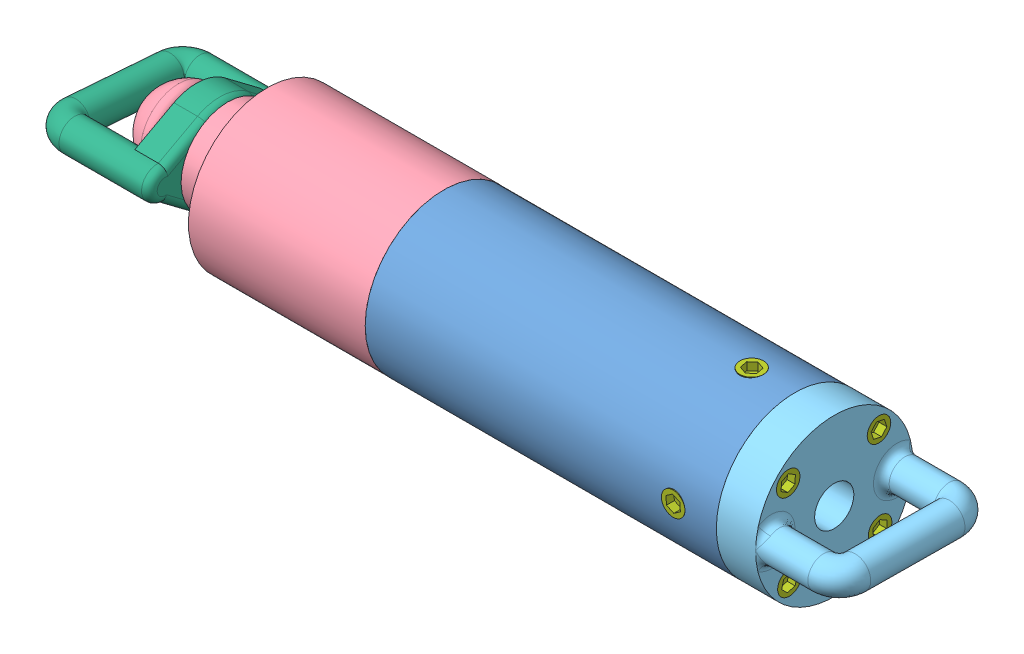
SolidWorks assembly Ensamblaje original vista conjunta, configuration Predeterminado. Lengths in mm.
Overall size (103.35 23.38 23.38).
16 component instances, 7 part files, 18 mates.
Components (placement in the parent):
- Elemento 1-1: Elemento 1 [Predeterminado] at (-42.454 6.1684 44.721) size (44.72 20 20)
- Elemento 2-1: Elemento 2 [Predeterminado] at (-6.254 6.1684 44.721) x (1 0 0) z (0 -0.9988 0.048973) size (5 12.09 12.06)
- Elemento 3-1: Elemento 3 [Predeterminado] at (-3.254 6.1684 44.721) x (-1 0 0) z (0 -1 0) size (57.07 12 12)
- Elemento 4-1: Elemento 4 [Predeterminado] at (-42.454 6.1684 44.721) x (-1 0 0) z (0 0.982476 -0.186391) size (37.67 20 20)
- Elemento 5-1: Elemento 5 [Predeterminado] at (2.246 6.1684 44.721) x (1 0 0) z (0 0.009186 0.999958) size (15.81 20 20)
- Elemento 6-1: Elemento 6 [Predeterminado] at (-69.954 6.1684 44.721) x (-1 0 0) z (0 0.0753 0.997161) size (15.5 12.01 20.01)
- Tornillo-2: Tornillo [Predeterminado] at (-3.254 6.1684 34.721) x (0 0 1) z (-0.99419 -0.107636 0) size (6.53 3 3)
- Tornillo-3: Tornillo [Predeterminado] at (-3.254 6.1684 54.721) x (0 0 -1) z (0.285128 -0.958489 0) size (6.53 3 3)
- Tornillo-4: Tornillo [Predeterminado] at (-3.254 16.1684 44.721) x (0 -1 0) z (0.385697 0 0.922626) size (6.53 3 3)
- Tornillo-6: Tornillo [Predeterminado] at (-3.254 -3.8831 44.721) x (0 1 0) z (-0.159624 0 0.987178) size (6.53 3 3)
- Tornillo-7: Tornillo [Predeterminado] at (7.246 11.7663 39.0194) x (-1 0 0) z (0 0 -1) size (6.53 3 3)
- Tornillo-8: Tornillo [Predeterminado] at (7.246 0.7272 38.8697) x (-1 0 0) z (0 -0.269093 -0.963114) size (6.53 3 3)
- Tornillo-9: Tornillo [Predeterminado] at (7.246 0.5706 50.4226) x (-1 0 0) z (0 -0.539826 -0.841777) size (6.53 3 3)
- Tornillo-10: Tornillo [Predeterminado] at (7.246 11.6096 50.5723) x (-1 0 0) z (0 -0.345496 -0.93842) size (6.53 3 3)
- Tornillo-13: Tornillo [Predeterminado] at (-42.454 10.9184 44.721) size (6.53 3 3)
- Tornillo-14: Tornillo [Predeterminado] at (-42.454 1.4184 44.721) x (1 0 0) z (0 -0.491861 0.870674) size (6.53 3 3)
Mates (geometry in assembly coordinates):
- Concéntrica18: concentric anti-aligned: circle of Elemento 1-1; circle of Elemento 3-1
- Coincidente14: coincident anti-aligned: plane of Elemento 1-1 through (-40.454 6.1684 44.721) normal (1 0 0); plane of Elemento 3-1 through (-40.454 6.1684 44.721) normal (-1 0 0)
- Concéntrica19: concentric anti-aligned: circle of Elemento 1-1; circle of Tornillo-13
- Coincidente16: coincident anti-aligned: plane of Elemento 1-1 through (-42.454 -3.9516 54.841) normal (-1 0 0); circle of Tornillo-13
- Coincidente17: coincident anti-aligned: plane of Elemento 1-1 through (-42.454 -3.9516 54.841) normal (-1 0 0); circle of Tornillo-14
- Coincidente18: coincident anti-aligned: circle of Elemento 1-1; circle of Elemento 4-1
- Coincidente19: coincident anti-aligned: circle of Elemento 4-1; circle of Elemento 6-1
- Concéntrica20: concentric anti-aligned: cylinder of Elemento 1-1 through (-39.454 6.1684 44.721) axis (1 0 0) radius 6; cylinder of Elemento 2-1 through (-1.254 6.1684 44.721) axis (-1 0 0) radius 6
- Coincidente20: coincident anti-aligned: plane of Elemento 2-1 through (-6.254 -0.1937 38.9537) normal (-1 0 0); plane of Elemento 3-1 through (-6.254 6.1684 44.721) normal (1 0 0)
- Coincidente21: coincident aligned: cylinder of Elemento 1-1 through (-3.254 0.3589 44.721) axis (0 1 0) radius 1.5; circle of Tornillo-6
- Tangente8: tangent: curve of Elemento 1-1; circle of Tornillo-4
- Tangente9: tangent: curve of Elemento 1-1; circle of Tornillo-3
- Tangente10: tangent: curve of Elemento 1-1; circle of Tornillo-2
- Coincidente22: coincident aligned: circle of Elemento 1-1; circle of Elemento 5-1
- Coincidente23: coincident anti-aligned: circle of Elemento 5-1; circle of Tornillo-7
- Coincidente24: coincident anti-aligned: circle of Elemento 5-1; circle of Tornillo-10
- Coincidente25: coincident anti-aligned: circle of Elemento 5-1; circle of Tornillo-8
- Coincidente26: coincident anti-aligned: circle of Elemento 5-1; circle of Tornillo-9
